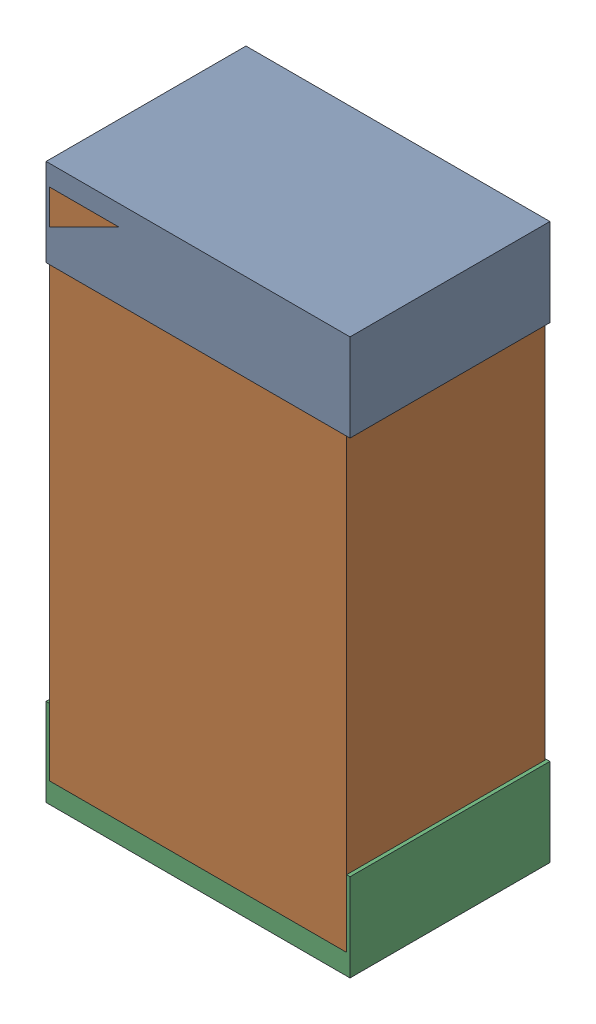
SolidWorks assembly R20Kanaloa_v2.0.0_Motor, configuration Default. Lengths in mm.
Overall size (1.3 2.38 0.85).
6 component instances, 2 part files, 0 mates.
Components (placement in the parent):
- 330415056-1: 330415056 [Default] at (123.952 70.85 -1.9574) size (1.3 0.38 0.85)
  - Extruded_2-1: Extruded_2 [Default] at origin size (1.3 0.38 0.85)
- 334787376-1: 334787376 [Default] at (123.952 69.85 -1.9524) size (1.27 2.2 0.85)
  - Extruded_16-1: Extruded_16 [Default] at origin size (1.27 2.2 0.85)
- 330415056-2: 330415056 [Default] at (123.952 68.85 -1.9574) size (1.3 0.38 0.85)
  - Extruded_2-1: Extruded_2 [Default] at origin size (1.3 0.38 0.85)
